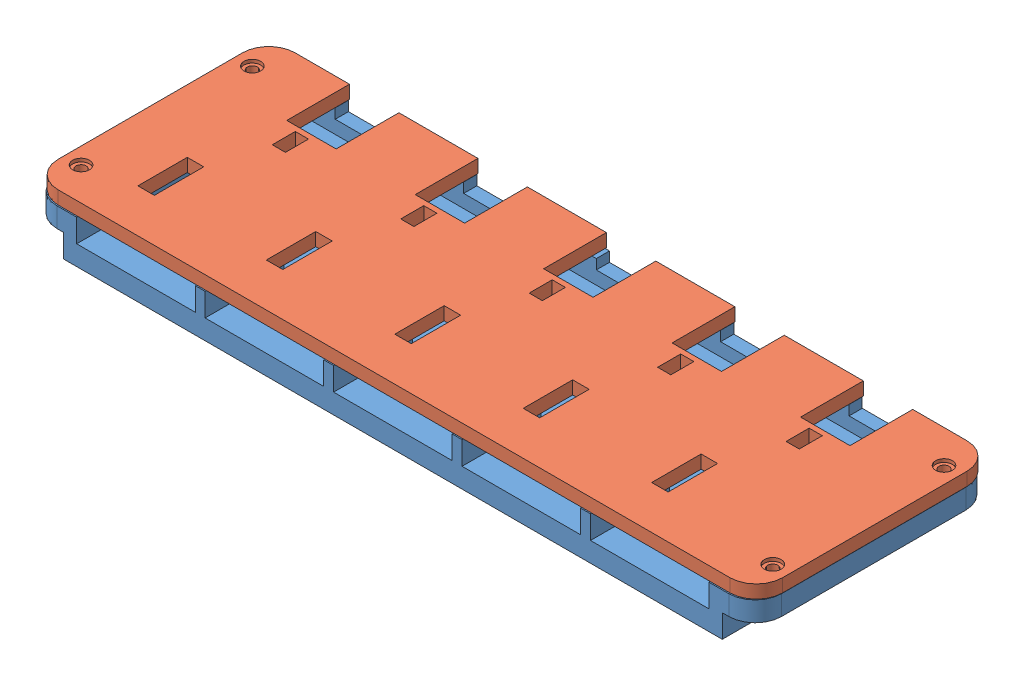
SolidWorks assembly Assem1_receivers_holder, configuration По умолчанию. Lengths in mm.
Overall size (110.02 11.5 36.19).
2 component instances, 2 part files, 1 mates.
Components (placement in the parent):
- holder_for_adc_part1-1: holder_for_adc_part1 [По умолчанию] at (47.5767 53.3626 46.3749) size (110 9.5 36)
- holder_for_adc_part2-1: holder_for_adc_part2 [По умолчанию] at (45.147 59.8626 44.441) size (110 2 36)
Mates (geometry in assembly coordinates):
- Coincident1: coincident anti-aligned: plane of holder_for_adc_part1-1 through (47.5767 59.8626 46.3749) normal (0 1 0); plane of holder_for_adc_part2-1 through (9.6344 59.8626 41.7429) normal (0 -1 0)
